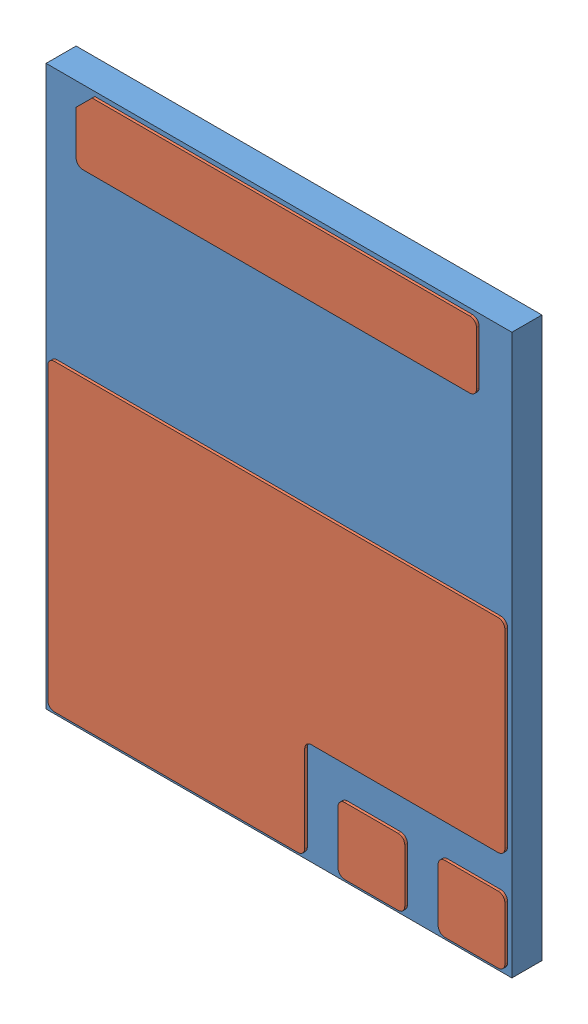
SolidWorks assembly Gan, configuration Default. Lengths in mm.
Overall size (6.98 8.38 0.49).
2 component instances, 2 part files, 0 mates.
Components (placement in the parent):
- Package-1: Package [Default] at (-0.2715 0.0344 6.2506) size (6.98 8.38 0.45)
- PCB Bottom CDMM-1: PCB Bottom CDMM [Default] at (-0.0115 0.0344 6.7006) size (6.85 8.25 0.04)
